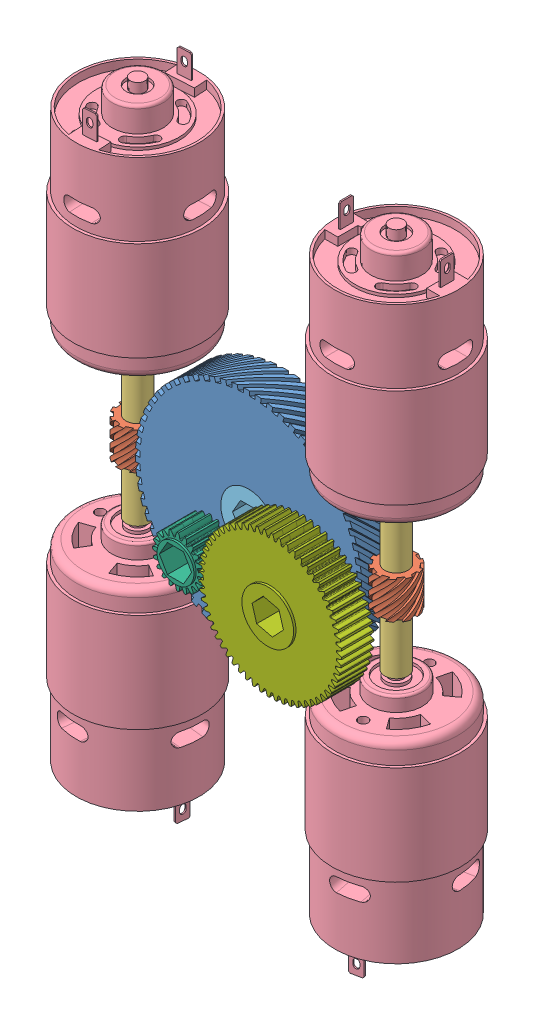
SolidWorks assembly Assem1, configuration Default. Lengths in mm.
Overall size (139.33 214.37 57.54).
12 component instances, 7 part files, 27 mates.
Components (placement in the parent):
- Large Helical Gear-1: Large Helical Gear [Default] at (0 0 -6.35) x (1 0 0) z (0 1 0) size (79 12.79 79)
- Small Helical Gear-1: Small Helical Gear [Default] at (-44.45 6.35 0) x (0.992078 0 -0.125626) z (0.125626 0 0.992078) size (14.92 12.75 14.72)
- Small Helical Gear-2: Small Helical Gear [Default] at (44.45 6.35 0) x (-0.822934 0 -0.568138) z (0.568138 0 -0.822934) size (14.92 12.75 14.72)
- Motor Shaft-1: Motor Shaft [Default] at (44.45 0.2924 0) x (0 1 0) z (0 0 1) size (50.8 7.94 7.94)
- Motor Shaft-2: Motor Shaft [Default] at (-44.45 1.229 0) x (0 1 0) z (0 0 1) size (50.8 7.94 7.94)
- 775Pro-1: 775Pro [Default] at (44.45 32.2799 0) x (0 1 0) z (0 0 1) size (88 44.3 44.3)
- 775Pro-2: 775Pro [Default] at (44.45 -31.6951 0) x (0 -1 0) z (0.980697 0 -0.195535) size (88 44.3 44.3)
- 775Pro-3: 775Pro [Default] at (-44.45 -30.7585 0) x (0 -1 0) z (-0.106276 0 0.994337) size (88 44.3 44.3)
- 775Pro-4: 775Pro [Default] at (-44.45 31.629 0) x (0 1 0) z (0.998378 0 -0.056933) size (88 44.3 44.3)
- Shaft Adapter-1: Shaft Adapter [Default] at (0 0 -6.35) x (-1 0 0) z (0 0 1) size (19.05 20.64 12.7)
- WCP-0005-1: WCP-0005 [Default] at (0 0 25.134) x (0 0 -1) z (1 0 0) size (12.65 17.46 17.46)
- WCP-0008-1: WCP-0008 [Default] at (31.75 0 25.1594) x (0 0 -1) z (0.972641 -0.232315 0) size (12.65 49.21 49.21)
Mates (geometry in assembly coordinates):
- Distance1: distance = 6.35 mm anti-aligned: plane of Large Helical Gear-1 through (0 0 -6.35) normal (0 0 -1); plane of assembly through (0 0 0) normal (0 0 1)
- Coincident2: coincident: line of Small Helical Gear-2 through (44.45 6.35 0) axis (0 1 0); plane of assembly
- Parallel1: parallel: line of Small Helical Gear-2 through (44.45 6.35 0) axis (0 1 0); plane of assembly
- Distance2: distance = 44.45 mm: line of Small Helical Gear-2 through (44.45 6.35 0) axis (0 1 0); line of Large Helical Gear-1 through (0 0 -6.35) axis (0 0 -1)
- Coincident4: coincident: line of Large Helical Gear-1 through (0 0 -6.35) axis (0 0 -1); plane of Small Helical Gear-2
- Coincident5: coincident aligned: plane of Small Helical Gear-1 through (-44.45 -6.35 0) normal (0 -1 0); plane of Small Helical Gear-2 through (44.45 -6.35 0) normal (0 -1 0)
- Coincident6: coincident: line of Small Helical Gear-1 through (6.2471 -44.45 6.35) axis (0 0 1); plane of assembly
- Distance3: distance = 44.45 mm: line of Small Helical Gear-1 through (6.2471 -44.45 6.35) axis (0 0 1); line of Large Helical Gear-1 through (0 0 -6.35) axis (0 0 -1)
- Coincident8: coincident: line of Large Helical Gear-1 through (0 0 -6.35) axis (0 0 -1); plane of assembly
- Coincident9: coincident: line of Large Helical Gear-1 through (0 0 -6.35) axis (0 0 -1); plane of assembly
- Concentric1: concentric aligned: cylinder of Motor Shaft-1 through (44.45 25.6924 0) axis (0 -1 0) radius 3.9688; cylinder of 775Pro-1 through (44.45 32.2799 0) axis (0 -1 0) radius 2.5
- Distance4: distance = 1.5875 mm anti-aligned: plane of 775Pro-1 through (41.95 27.2799 0) normal (0 -1 0); plane of Motor Shaft-1 through (44.45 25.6924 0) normal (0 1 0)
- Concentric2: concentric anti-aligned: cylinder of Motor Shaft-1 through (44.45 25.6924 0) axis (0 -1 0) radius 3.9688; cylinder of 775Pro-2 through (44.45 -31.6951 0) axis (0 1 0) radius 2.5
- Distance5: distance = 1.5875 mm anti-aligned: plane of 775Pro-2 through (43.9612 -26.6951 -2.4517) normal (0 1 0); plane of Motor Shaft-1 through (44.45 -25.1076 0) normal (0 -1 0)
- Concentric3: concentric anti-aligned: line of Small Helical Gear-2 through (44.45 6.35 0) axis (0 1 0); cylinder of Motor Shaft-1 through (44.45 25.6924 0) axis (0 -1 0) radius 3.9688
- Concentric4: concentric anti-aligned: line of Small Helical Gear-1 through (6.2471 -44.45 6.35) axis (0 0 1); cylinder of Motor Shaft-2 through (-44.45 26.629 0) axis (0 -1 0) radius 3.9688
- Concentric5: concentric anti-aligned: cylinder of Motor Shaft-2 through (-44.45 -11.471 0) axis (0 -1 0) radius 2.5; cylinder of 775Pro-3 through (-44.45 -30.7585 0) axis (0 1 0) radius 2.5
- Distance6: distance = 1.5875 mm anti-aligned: plane of 775Pro-3 through (-41.9642 -25.7585 0.2657) normal (0 1 0); plane of Motor Shaft-2 through (-44.45 -24.171 0) normal (0 -1 0)
- Concentric6: concentric aligned: cylinder of Motor Shaft-2 through (-44.45 26.629 0) axis (0 -1 0) radius 3.9688; cylinder of 775Pro-4 through (-44.45 31.629 0) axis (0 -1 0) radius 2.5
- Coincident14: coincident anti-aligned: plane of Motor Shaft-2 through (-44.45 26.629 0) normal (0 1 0); plane of 775Pro-4 through (-44.3077 26.629 2.4959) normal (0 -1 0)
- Concentric7: concentric aligned: line of Large Helical Gear-1 through (0 0 -6.35) axis (0 0 -1); cylinder of Shaft Adapter-1 through (0 0 6.35) axis (0 0 -1) radius 9.525
- Coincident15: coincident anti-aligned: plane of Large Helical Gear-1 through (1.5875 -11.1125 6.4309) normal (-1 0 0); plane of Shaft Adapter-1 through (1.5875 -11.1125 6.35) normal (1 0 0)
- Coincident16: coincident aligned: plane of Large Helical Gear-1 through (0 0 -6.35) normal (0 0 -1); plane of Shaft Adapter-1 through (0 0 -6.35) normal (0 0 -1)
- Concentric8: concentric anti-aligned: line of Large Helical Gear-1 through (0 0 -6.35) axis (0 0 -1); circle of WCP-0005-1
- Coincident17: coincident aligned: plane of WCP-0005-1 through (0 0 30.6902) normal (0 0 1); plane of WCP-0008-1 through (31.75 0 30.6902) normal (0 0 1)
- Distance8: distance = 31.75 mm: axis of WCP-0008-1 through (31.75 0 30.6902) axis (0 0 -1); axis of WCP-0005-1 through (0 0 19.5777) axis (0 0 1)
- Coincident19: coincident: axis of WCP-0008-1 through (31.75 0 30.6902) axis (0 0 -1); plane of assembly
